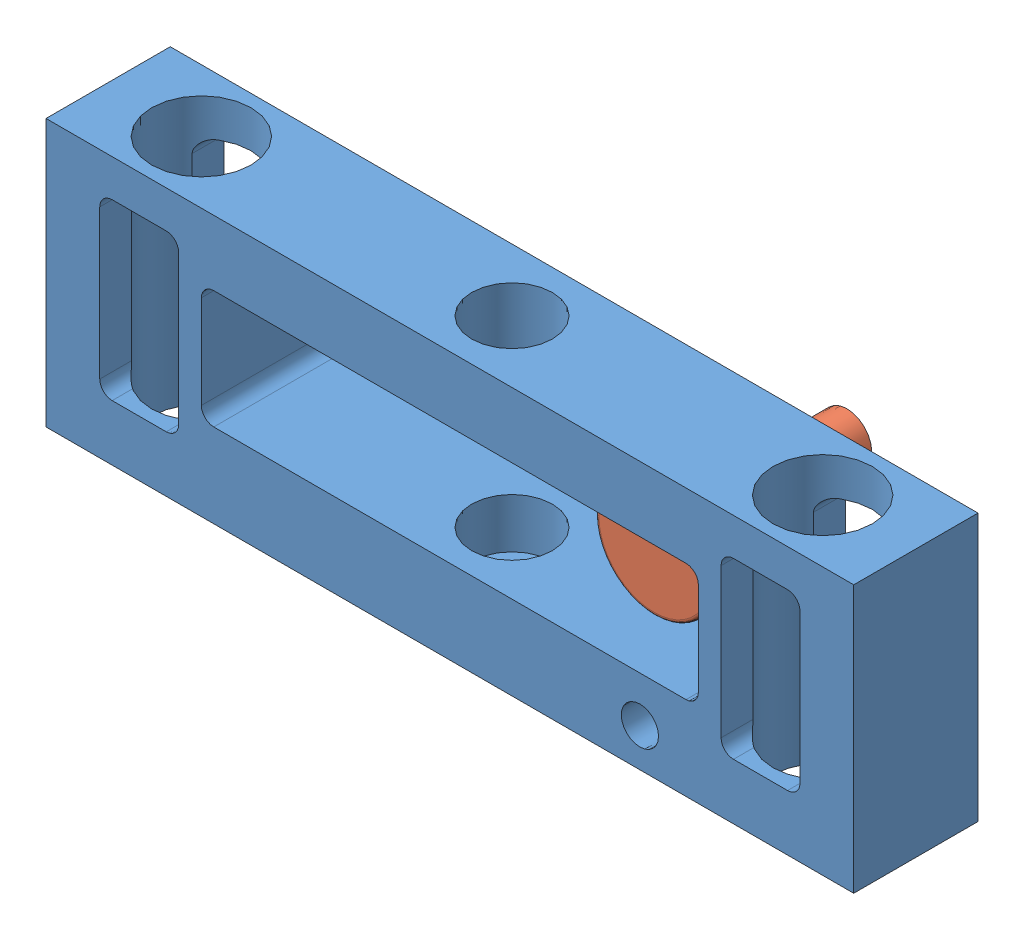
SolidWorks assembly Cam Follower Assem, configuration Default. Lengths in mm.
2 component instances, 2 part files, 4 mates.
Components (placement in the parent):
- Linear Slider Crank bozx-1: Linear Slider Crank bozx [Default] at (0 14.2712 0) size (130 50 20)
- Cam Follower-1: Cam Follower [Default] at (23.8971 14.2712 -10) size (19 19 31)
Mates (geometry in assembly coordinates):
- Coincident2: coincident anti-aligned: plane of Linear Slider Crank bozx-1; plane of assembly through (0 0 0) normal (1 0 0)
- Coincident3: coincident aligned: plane of Linear Slider Crank bozx-1 through (0 37.164 0) normal (0 0 1); plane of assembly through (0 0 0) normal (0 0 1)
- Coincident4: coincident: line of Linear Slider Crank bozx-1 through (-27 37.164 -5) axis (1 0 0); plane of Cam Follower-1 through (-20.9928 37.164 -14) normal (0 1 0)
- LimitDistance1: limit distance = -20.9928 mm: point of ?
